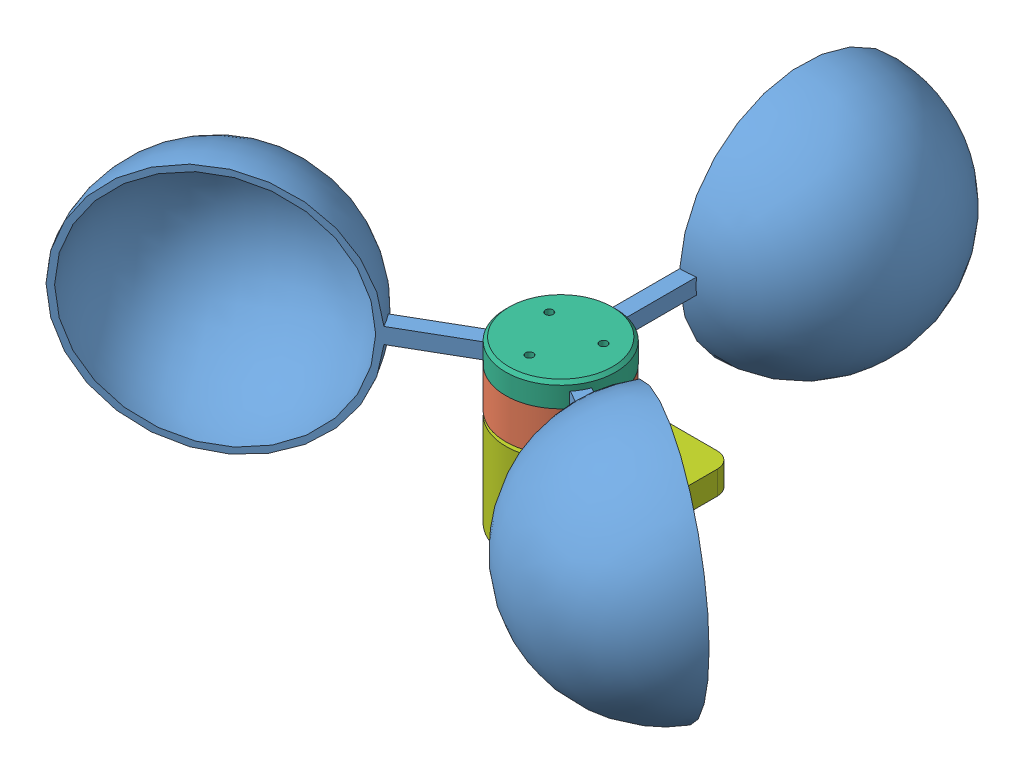
SolidWorks assembly anemometer assembly, configuration По умолчанию. Lengths in mm.
Overall size (90.69 37.2 84.47).
12 component instances, 9 part files, 25 mates.
Components (placement in the parent):
- cup-1: cup [По умолчанию] at (-14.1975 6 9.4093) x (0 1 0) z (-0.866025 0 0.5) size (31.6 15.8 45.8)
- rotor-1: rotor [По умолчанию] at origin size (14 5.1 14)
- cup-4: cup [По умолчанию] at (-1.0499 6 -17.0001) x (0 1 0) z (0 0 -1) size (31.6 15.8 45.8)
- cup-5: cup [По умолчанию] at (15.2475 6 7.5908) x (0 1 0) z (0.866025 0 0.5) size (31.6 15.8 45.8)
- axis-1: axis [По умолчанию] at (0 -15.4 0) x (-0.535206 0 -0.844722) z (0.844722 0 -0.535206) size (2 23 2)
- magnet-1: magnet [По умолчанию] at (-0.1 2.25 5.6) x (1 0 0) z (0 -1 0) size (3.5 0.7 3.5)
- bearing-1: bearing [По умолчанию] at (0 -2.5 0) x (0.586698 0 -0.809806) z (0.809806 0 0.586698) size (5 2.5 5)
- bearing-2: bearing [По умолчанию] at (0 -12.5 0) size (5 2.5 5)
- rayholder-1: rayholder [По умолчанию] at (0 5.1 0) x (0.5 0 0.866025) z (-0.866025 0 0.5) size (14 3 14)
- base-1: base [По умолчанию] at (0 0.5 0) x (0 0 -1) z (-1 0 0) size (22 13 14)
- lock-1: lock [По умолчанию] at (0 -14.5 0) size (4 2 4)
- ss441a-1: ss441a [По умолчанию] at (-3.6804 0 0.25) x (0 0 1) z (-1 0 0) size (4 3 1.5)
Mates (geometry in assembly coordinates):
- Совпадение1: coordinate: point of ротор-1
- Концентричный1: concentric aligned: cylinder of ротор-1 through (0 8 0) axis (0 -1 0) radius 0.95; cylinder of ось-1 through (0 7.6 0) axis (0 -1 0) radius 1
- Концентричный2: concentric aligned: cylinder of ось-1 through (0 7.6 0) axis (0 -1 0) radius 1; cylinder of подшипник-1 through (0 0 0) axis (0 -1 0) radius 1
- Концентричный3: concentric aligned: cylinder of ось-1 through (0 7.6 0) axis (0 -1 0) radius 1; cylinder of подшипник-2 through (0 -10 0) axis (0 -1 0) radius 1
- Концентричный4: concentric aligned: cylinder of ось-1 through (0 7.6 0) axis (0 -1 0) radius 1; cylinder of rayholder-1 through (0 5.1 0) axis (0 -1 0) radius 1.05
- Совпадение9: coincident anti-aligned: plane of ротор-1 through (0 5.1 0) normal (0 1 0); plane of rayholder-1 through (0 5.1 0) normal (0 -1 0)
- Совпадение10: coincident anti-aligned: plane of лопатка-4 through (0.9501 7 -17.0001) normal (0 1 0); plane of rayholder-1 through (0 7 0) normal (0 -1 0)
- Совпадение11: coincident anti-aligned: plane of ротор-1 through (0 4 0) normal (0 -1 0); plane of магнит-1 through (-1.85 4 6.3) normal (0 1 0)
- Совпадение12: coincident anti-aligned: plane of ротор-1 through (-1.85 4 6.3) normal (0 0 -1); plane of магнит-1 through (-0.1 2.25 6.3) normal (0 0 1)
- Совпадение13: coincident anti-aligned: plane of ротор-1 through (-1.85 4 6.3) normal (1 0 0); plane of магнит-1 through (-1.85 0.5 6.3) normal (-1 0 0)
- Параллельность4: parallel anti-aligned: plane of base-1 through (0 -12.5 0) normal (0 -1 0)
- Параллельность3: parallel anti-aligned: plane of base-1 through (-7 -12.5 0) normal (-1 0 0)
- Совпадение17: coincident anti-aligned: plane of лопатка-1 through (-14.1975 6 9.4093) normal (0.5 0 0.866025); plane of rayholder-1 through (-9.8673 7 6.9093) normal (-0.5 0 -0.866025)
- Расстояние2: distance = 12.5 mm anti-aligned: plane of подшипник-1 through (0 0 0) normal (0 1 0); plane of подшипник-2 through (0 -12.5 0) normal (0 -1 0)
- Совпадение19: coincident anti-aligned: plane of rotor-1 through (0 0 0) normal (0 -1 0); circle of подшипник-1
- Концентричный7: concentric anti-aligned: cylinder of ось-1 through (0 7.6 0) axis (0 -1 0) radius 1; cylinder of base-1 through (0 -12.5 0) axis (0 1 0) radius 2.5
- Совпадение20: coincident aligned: plane of подшипник-1 through (0 0 0) normal (0 1 0); plane of base-1 through (0 0 0) normal (0 1 0)
- Концентричный8: concentric aligned: cylinder of ось-1 through (0 7.6 0) axis (0 -1 0) radius 1; cylinder of stopor-1 through (0 -12.5 0) axis (0 -1 0) radius 0.95
- Совпадение21: coincident anti-aligned: plane of подшипник-2 through (0 -12.5 0) normal (0 -1 0); plane of stopor-1 through (0 -12.5 0) normal (0 1 0)
- Совпадение23: coincident anti-aligned: plane of лопатка-4 through (0.9501 7 -2.0001) normal (0 0 1); plane of rayholder-1 through (1.05 7 -2.0001) normal (0 0 -1)
- Концентричный13: concentric aligned: cylinder of rotor-1 through (3.4641 5.1 -2) axis (0 -1 0) radius 0.9; cylinder of rayholder-1 through (3.4641 8.1 -2) axis (0 -1 0) radius 0.5
- Совпадение25: coincident anti-aligned: plane of ось-1 through (0 7.6 0) normal (0 1 0); plane of rayholder-1 through (0 7.6 0) normal (0 -1 0)
- Совпадение26: coincident anti-aligned: plane of base-1 through (-3.6804 -1.5 2.25) normal (-1 0 0); plane of ss441a-1 through (-3.6804 0 0.25) normal (1 0 0)
- Совпадение27: coincident anti-aligned: plane of base-1 through (0 -1.5 0) normal (0 1 0); plane of ss441a-1 through (-5.1804 -1.5 -1.75) normal (0 -1 0)
- Совпадение28: coincident anti-aligned: plane of base-1 through (-5.6736 -1.5 2.25) normal (0 0 -1); plane of ss441a-1 through (-5.1804 -1.5 2.25) normal (0 0 1)
